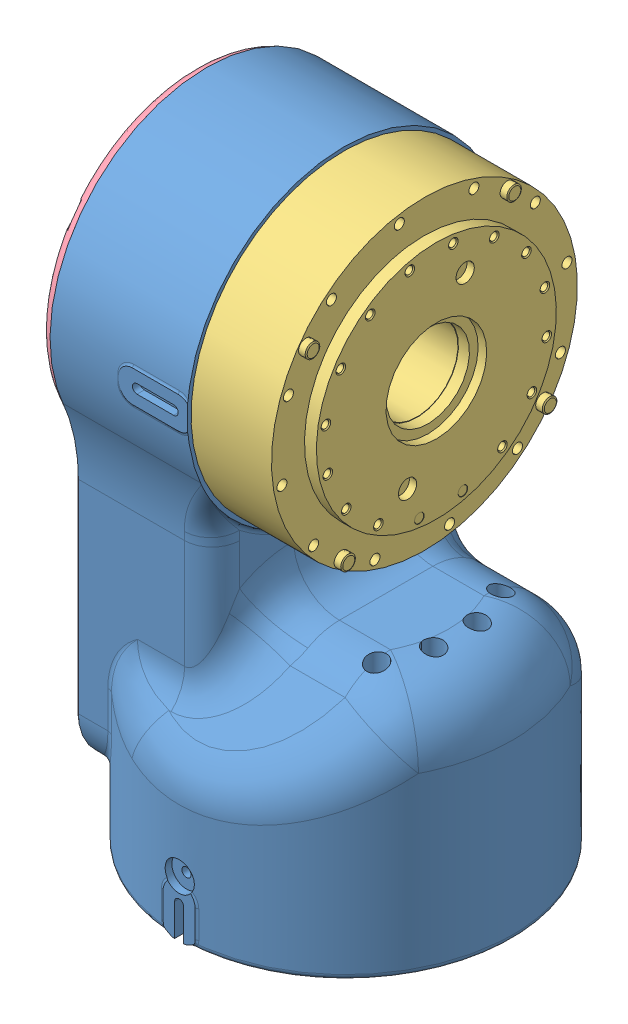
SolidWorks assembly ASM-EX__ASM, configuration Valor predeterminado. Lengths in mm.
Overall size (196.29 342.46 193.46).
4 component instances, 4 part files, 0 mates.
Components (placement in the parent):
- LARM_B_-1: LARM_B_ [Valor predeterminado] at origin size (182 331.23 188.66)
- 0411583_1_-1: 0411583_1_ [Valor predeterminado] at (0 40.2614 0) x (0 -1 0) z (0 0 1) size (9 90 90)
- AC32_-1: AC32_ [Valor predeterminado] at (-1 224.1 0) x (0 0.173648 -0.984808) z (-1 0 0) size (167 167 121.2)
- L_B_COVER_-1: L_B_COVER_ [Valor predeterminado] at (-76 224.1 0) x (0 0 -1) z (1 0 0) size (170.58 299.9 38.13)
